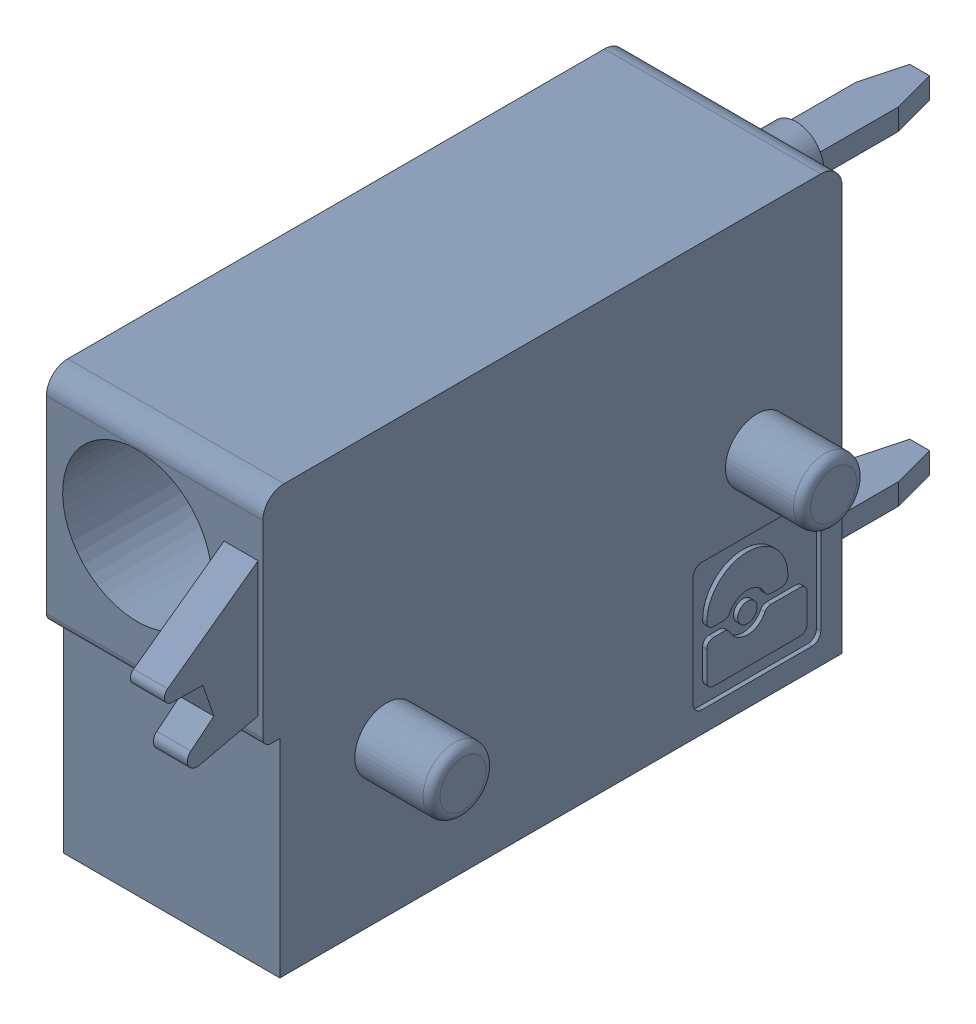
SolidWorks assembly J12, configuration Default. Lengths in mm.
Overall size (6.88 10 19.2).
2 component instances, 1 part files, 0 mates.
Components (placement in the parent):
- 1790348-1: 1790348 [Default] at (24.7651 -7.6199 0) x (0 1 0) z (1 0 0) size (10 19.2 6.88)
  - ffkds-v2-5.08-1: ffkds-v2-5.08 [Default] at (-23.7414 -38.158 -2.54) x (0 -1 0) z (0 0 1) size (19.2 10 6.88)
